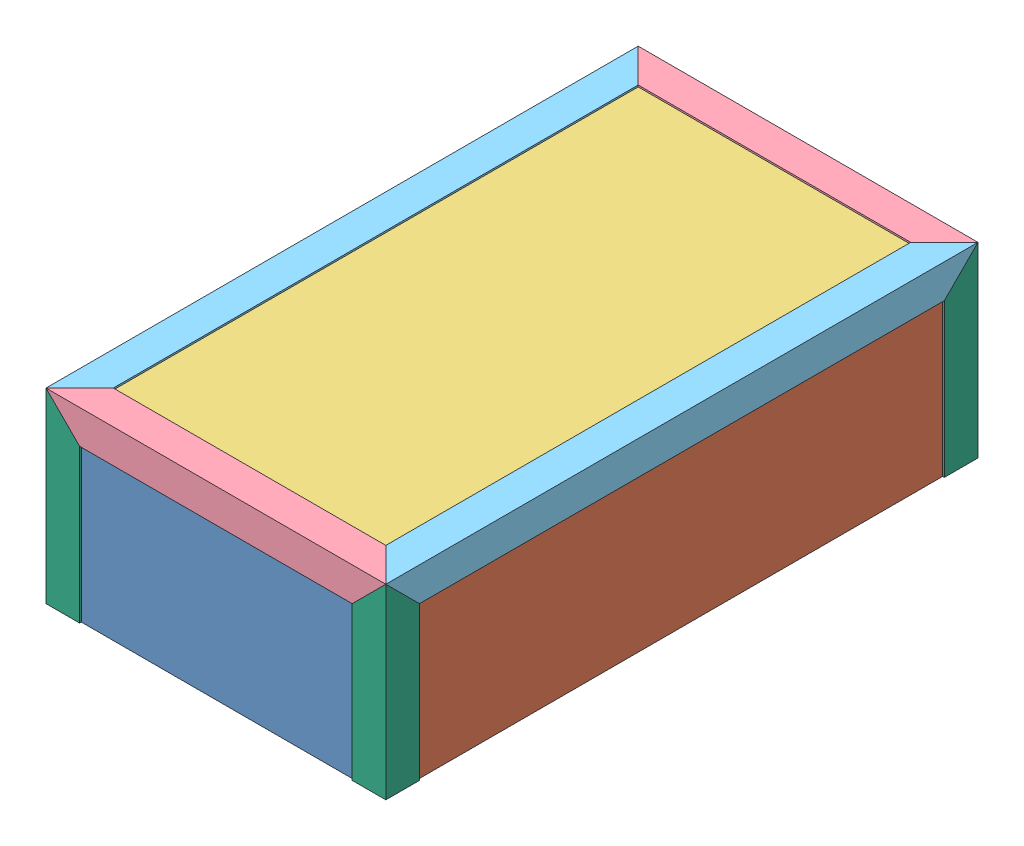
SolidWorks assembly couvercle, configuration Défaut. Lengths in mm.
Overall size (404 222 704).
13 component instances, 6 part files, 38 mates.
Components (placement in the parent):
- plaque_acrylique_380x210-1: plaque_acrylique_380x210 [Défaut] at (-187.4996 -8.7215 -5) size (380 210 10)
- plaque_acrylique_680x210-1: plaque_acrylique_680x210 [Défaut] at (2.5004 -8.7215 -345) x (0 0 -1) z (1 0 0) size (680 210 10)
- plaque_acrylique_680x210-2: plaque_acrylique_680x210 [Défaut] at (-387.4996 -8.7215 -345) x (0 0 -1) z (1 0 0) size (680 210 10)
- plaque_acrylique_380x210-2: plaque_acrylique_380x210 [Défaut] at (-187.4996 -8.7215 -695) size (380 210 10)
- plaque_acrylique_380x680-1: plaque_acrylique_380x680 [Défaut] at (-187.4996 96.2785 -345) x (1 0 0) z (0 1 0) size (380 680 10)
- eclisse_40x40x404_bisote_x2-1: eclisse_40x40x404_bisote_x2 [Défaut] at (14.5004 88.1649 -677) x (0 0 1) z (0 -1 0) size (40 404 40)
- eclisse_40x40x704_bisote_x2-1: eclisse_40x40x704_bisote_x2 [Défaut] at (-5.6132 88.2785 -697) x (0 -1 0) z (-1 0 0) size (40 704 40)
- eclisse_40x40x404_bisote_x2-2: eclisse_40x40x404_bisote_x2 [Défaut] at (-389.4996 88.1649 -13) x (0 0 -1) z (0 -1 0) size (40 404 40)
- eclisse_40x40x704_bisote_x2-2: eclisse_40x40x704_bisote_x2 [Défaut] at (-369.4996 88.1649 -697) x (1 0 0) z (0 -1 0) size (40 704 40)
- eclisse_40x40x222_bisote_x1-1: eclisse_40x40x222_bisote_x1 [Défaut] at (-369.386 108.2785 -677) x (0 0 1) z (1 0 0) size (40 222 40)
- eclisse_40x40x222_bisote_x1-2: eclisse_40x40x222_bisote_x1 [Défaut] at (-5.4996 108.2785 -676.8864) x (-1 0 0) z (0 0 1) size (40 222 40)
- eclisse_40x40x222_bisote_x1-3: eclisse_40x40x222_bisote_x1 [Défaut] at (-5.6132 108.2785 -13) x (0 0 -1) z (-1 0 0) size (40 222 40)
- eclisse_40x40x222_bisote_x1-4: eclisse_40x40x222_bisote_x1 [Défaut] at (-369.4996 108.2785 -13.1136) x (1 0 0) z (0 0 -1) size (40 222 40)
Mates (geometry in assembly coordinates):
- Parallèle1: parallel anti-aligned: plane of plaque_acrylique_680x210-1 through (2.5004 -8.7215 -345) normal (-1 0 0); plane of plaque_acrylique_680x210-2 through (-377.4996 -8.7215 -345) normal (1 0 0)
- Parallèle2: parallel anti-aligned: plane of plaque_acrylique_380x210-1 through (-187.4996 -8.7215 -5) normal (0 0 -1); plane of plaque_acrylique_380x210-2 through (-187.4996 -8.7215 -685) normal (0 0 1)
- Coïncidente3: coincident anti-aligned: plane of plaque_acrylique_680x210-1 through (12.5004 96.2785 -685) normal (0 0 -1); plane of plaque_acrylique_380x210-2 through (-187.4996 -8.7215 -685) normal (0 0 1)
- Coïncidente4: coincident anti-aligned: plane of plaque_acrylique_680x210-1 through (2.5004 -8.7215 -345) normal (-1 0 0); plane of plaque_acrylique_380x210-2 through (2.5004 96.2785 -685) normal (1 0 0)
- Coïncidente5: coincident anti-aligned: plane of plaque_acrylique_680x210-2 through (-377.4996 -8.7215 -345) normal (1 0 0); plane of plaque_acrylique_380x210-2 through (-377.4996 96.2785 -685) normal (-1 0 0)
- Coïncidente6: coincident anti-aligned: plane of plaque_acrylique_680x210-2 through (-377.4996 96.2785 -685) normal (0 0 -1); plane of plaque_acrylique_380x210-2 through (-187.4996 -8.7215 -685) normal (0 0 1)
- Coïncidente7: coincident anti-aligned: plane of plaque_acrylique_380x210-1 through (-187.4996 -8.7215 -5) normal (0 0 -1); plane of plaque_acrylique_680x210-2 through (-377.4996 96.2785 -5) normal (0 0 1)
- Coïncidente8: coincident anti-aligned: plane of plaque_acrylique_380x210-1 through (2.5004 96.2785 5) normal (1 0 0); plane of plaque_acrylique_680x210-1 through (2.5004 -8.7215 -345) normal (-1 0 0)
- Coïncidente9: coincident aligned: plane of plaque_acrylique_380x210-1 through (-377.4996 96.2785 5) normal (0 1 0); plane of plaque_acrylique_680x210-2 through (-377.4996 96.2785 -5) normal (0 1 0)
- Coïncidente10: coincident aligned: plane of plaque_acrylique_380x210-1 through (-377.4996 96.2785 5) normal (0 1 0); plane of plaque_acrylique_680x210-1 through (12.5004 96.2785 -5) normal (0 1 0)
- Coïncidente11: coincident aligned: plane of plaque_acrylique_680x210-1 through (12.5004 96.2785 -5) normal (0 1 0); plane of plaque_acrylique_380x210-2 through (-377.4996 96.2785 -685) normal (0 1 0)
- Coïncidente12: coincident anti-aligned: plane of plaque_acrylique_680x210-2 through (-377.4996 96.2785 -5) normal (0 1 0); plane of plaque_acrylique_380x680-1 through (-187.4996 96.2785 -345) normal (0 -1 0)
- Coïncidente13: coincident anti-aligned: plane of plaque_acrylique_680x210-1 through (2.5004 -8.7215 -345) normal (-1 0 0); plane of plaque_acrylique_380x680-1 through (2.5004 106.2785 -685) normal (1 0 0)
- Coïncidente14: coincident anti-aligned: plane of plaque_acrylique_380x210-2 through (-187.4996 -8.7215 -685) normal (0 0 1); plane of plaque_acrylique_380x680-1 through (-377.4996 106.2785 -685) normal (0 0 -1)
- Coïncidente15: coincident anti-aligned: plane of plaque_acrylique_380x680-1 through (-187.4996 106.2785 -345) normal (0 1 0); plane of eclisse_40x40x704_bisote_x2-2 through (-387.4996 106.2785 7) normal (0 -1 0)
- Coïncidente16: coincident anti-aligned: plane of plaque_acrylique_380x680-1 through (-187.4996 106.2785 -345) normal (0 1 0); plane of eclisse_40x40x704_bisote_x2-1 through (12.5004 106.2785 7) normal (0 -1 0)
- Coïncidente17: coincident anti-aligned: plane of plaque_acrylique_680x210-1 through (12.5004 -8.7215 -345) normal (1 0 0); plane of eclisse_40x40x704_bisote_x2-1 through (12.5004 106.2785 7) normal (-1 0 0)
- Coïncidente18: coincident anti-aligned: plane of plaque_acrylique_680x210-2 through (-387.4996 -8.7215 -345) normal (-1 0 0); plane of eclisse_40x40x704_bisote_x2-2 through (-387.4996 106.2785 7) normal (1 0 0)
- Coïncidente19: coincident anti-aligned: plane of plaque_acrylique_380x680-1 through (-187.4996 106.2785 -345) normal (0 1 0); plane of eclisse_40x40x404_bisote_x2-2 through (14.5004 106.2785 5) normal (0 -1 0)
- Coïncidente20: coincident anti-aligned: plane of plaque_acrylique_380x210-1 through (-187.4996 -8.7215 5) normal (0 0 1); plane of eclisse_40x40x404_bisote_x2-2 through (14.5004 106.2785 5) normal (0 0 -1)
- Coïncidente21: coincident anti-aligned: plane of plaque_acrylique_380x680-1 through (-187.4996 106.2785 -345) normal (0 1 0); plane of eclisse_40x40x404_bisote_x2-1 through (-389.4996 106.2785 -695) normal (0 -1 0)
- Coïncidente22: coincident anti-aligned: plane of plaque_acrylique_380x210-2 through (-187.4996 -8.7215 -695) normal (0 0 -1); plane of eclisse_40x40x404_bisote_x2-1 through (-389.4996 106.2785 -695) normal (0 0 1)
- Coïncidente25: coincident anti-aligned: plane of eclisse_40x40x404_bisote_x2-1 through (-389.4996 68.2785 -697) normal (-0.707107 0 0.707107); plane of eclisse_40x40x704_bisote_x2-2 through (-389.4996 -481.7215 -697) normal (0.707107 0 -0.707107)
- Coïncidente28: coincident: point of eclisse_40x40x404_bisote_x2-1; point of eclisse_40x40x704_bisote_x2-2
- Coïncidente29: coincident anti-aligned: plane of eclisse_40x40x404_bisote_x2-1 through (14.5004 -481.7215 -697) normal (0.707107 0 0.707107); plane of eclisse_40x40x704_bisote_x2-1 through (14.5004 -481.7215 -697) normal (-0.707107 0 -0.707107)
- Coïncidente30: coincident anti-aligned: plane of eclisse_40x40x704_bisote_x2-1 through (14.5004 68.2785 7) normal (-0.707107 0 0.707107); plane of eclisse_40x40x404_bisote_x2-2 through (14.5004 68.2785 7) normal (0.707107 0 -0.707107)
- Coïncidente31: coincident anti-aligned: plane of eclisse_40x40x704_bisote_x2-2 through (200.5004 108.2785 -697) normal (0 -0.707107 -0.707107); plane of eclisse_40x40x222_bisote_x1-1 through (200.5004 108.2785 -697) normal (0 0.707107 0.707107)
- Coïncidente33: coincident aligned: plane of eclisse_40x40x404_bisote_x2-1 through (-389.4996 108.2785 -697) normal (0 0 -1); plane of eclisse_40x40x222_bisote_x1-1 through (-389.4996 -113.7215 -697) normal (0 0 -1)
- Coïncidente34: coincident anti-aligned: plane of eclisse_40x40x404_bisote_x2-1 through (-389.4996 108.2785 -657) normal (-0.707107 -0.707107 0); plane of eclisse_40x40x222_bisote_x1-1 through (-389.4996 108.2785 -107) normal (0.707107 0.707107 0)
- Coïncidente35: coincident aligned: plane of eclisse_40x40x404_bisote_x2-1 through (-389.4996 108.2785 -697) normal (0 0 -1); plane of eclisse_40x40x222_bisote_x1-2 through (14.5004 -113.7215 -697) normal (0 0 -1)
- Coïncidente36: coincident anti-aligned: plane of eclisse_40x40x404_bisote_x2-1 through (14.5004 108.2785 -107) normal (0.707107 -0.707107 0); plane of eclisse_40x40x222_bisote_x1-2 through (14.5004 108.2785 -107) normal (-0.707107 0.707107 0)
- Coïncidente37: coincident aligned: plane of eclisse_40x40x704_bisote_x2-1 through (14.5004 108.2785 7) normal (1 0 0); plane of eclisse_40x40x222_bisote_x1-2 through (14.5004 -113.7215 -697) normal (1 0 0)
- Coïncidente38: coincident aligned: plane of eclisse_40x40x704_bisote_x2-1 through (14.5004 108.2785 7) normal (1 0 0); plane of eclisse_40x40x222_bisote_x1-3 through (14.5004 -113.7215 7) normal (1 0 0)
- Coïncidente39: coincident anti-aligned: plane of eclisse_40x40x704_bisote_x2-1 through (-25.4996 108.2785 7) normal (0 -0.707107 0.707107); plane of eclisse_40x40x222_bisote_x1-3 through (-575.4996 108.2785 7) normal (0 0.707107 -0.707107)
- Coïncidente40: coincident aligned: plane of eclisse_40x40x404_bisote_x2-2 through (14.5004 108.2785 7) normal (0 0 1); plane of eclisse_40x40x222_bisote_x1-3 through (14.5004 -113.7215 7) normal (0 0 1)
- Coïncidente41: coincident aligned: plane of eclisse_40x40x704_bisote_x2-2 through (-389.4996 108.2785 7) normal (-1 0 0); plane of eclisse_40x40x222_bisote_x1-4 through (-389.4996 -113.7215 7) normal (-1 0 0)
- Coïncidente42: coincident anti-aligned: plane of eclisse_40x40x704_bisote_x2-2 through (-349.4996 108.2785 7) normal (0 -0.707107 0.707107); plane of eclisse_40x40x222_bisote_x1-4 through (200.5004 108.2785 7) normal (0 0.707107 -0.707107)
- Coïncidente43: coincident aligned: plane of eclisse_40x40x404_bisote_x2-2 through (14.5004 108.2785 7) normal (0 0 1); plane of eclisse_40x40x222_bisote_x1-4 through (-389.4996 -113.7215 7) normal (0 0 1)
